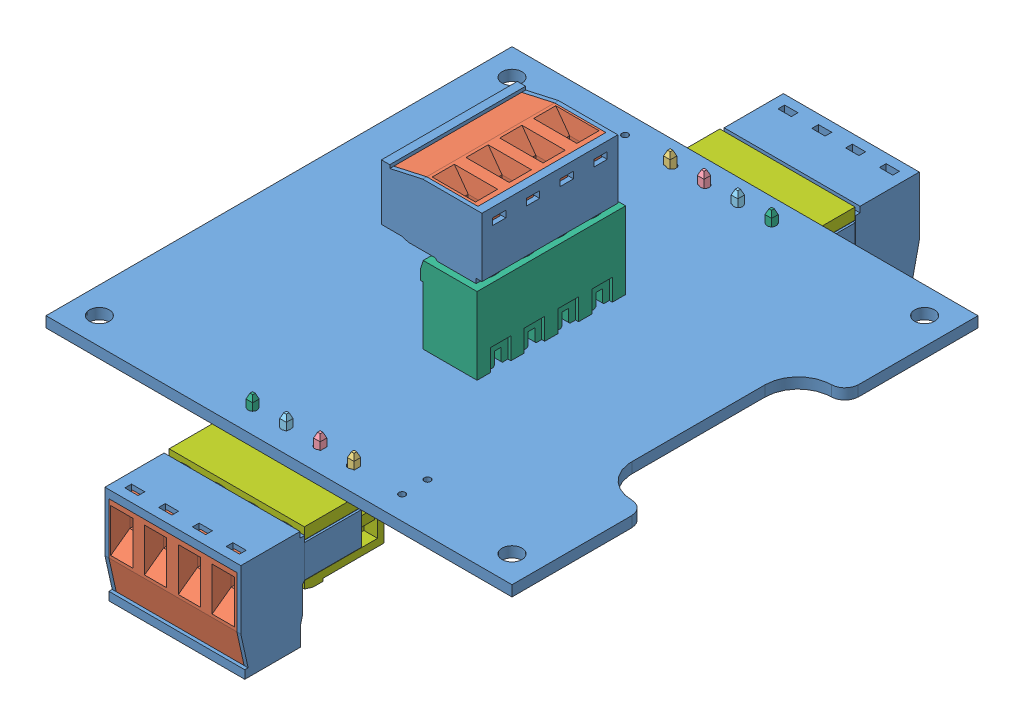
SolidWorks assembly MainBoard, configuration Default. Lengths in mm.
Overall size (70.02 38.08 102.19).
65 component instances, 26 part files, 22 mates.
Components (placement in the parent):
- MainBoard-1: MainBoard [Default] at origin size (70.02 1.6 70.02)
- 691311500104-1: 691311500104 [Default] at (1.7397 7.15 -0.127) x (0 0 1) z (0 1 0) size (22.32 8.5 16)
  - 691311500104_01-1: 691311500104_01 [Default] at origin size (1 1 15)
  - 691311500104_02-1: 691311500104_02 [Default] at origin size (1 1 15)
  - 691311500104_03-1: 691311500104_03 [Default] at origin size (1 1 15)
  - 691311500104_04-1: 691311500104_04 [Default] at origin size (1 1 15)
  - 691311500104_05-1: 691311500104_05 [Default] at origin size (22.32 8.5 12)
- 691351500004-1: 691351500004 [Default] at (1.1147 18.3 -0.127) x (0 0 -1) z (-1 0 0) size (20.42 18.2 15.1)
  - 691351500004_01-1: 691351500004_01 [Default] at origin size (3.9 4.9 7)
  - 691351500004_02-1: 691351500004_02 [Default] at origin size (3.9 4.9 7)
  - 691351500004_03-1: 691351500004_03 [Default] at origin size (3.9 4.9 7)
  - 691351500004_04-1: 691351500004_04 [Default] at origin size (3.9 4.9 7)
  - 691351500004_05-1: 691351500004_05 [Default] at origin size (3.41 13.5 4.75)
  - 691351500004_06-1: 691351500004_06 [Default] at origin size (3.41 13.5 4.75)
  - 691351500004_07-1: 691351500004_07 [Default] at origin size (3.41 13.5 4.75)
  - 691351500004_08-1: 691351500004_08 [Default] at origin size (3.41 13.5 4.75)
  - 691351500004_09-1: 691351500004_09 [Default] at origin size (3.8 3.8 6.92)
  - 691351500004_10-1: 691351500004_10 [Default] at origin size (3.8 3.8 6.92)
  - 691351500004_11-1: 691351500004_11 [Default] at origin size (3.8 3.8 6.92)
  - 691351500004_12-1: 691351500004_12 [Default] at origin size (3.8 3.8 6.92)
  - 691351500004_13-1: 691351500004_13 [Default] at origin size (20.42 18.2 15.1)
  - 691351500004_14-1: 691351500004_14 [Default] at origin size (19.22 3 13.65)
- 691351500004-2: 691351500004 [Default] at (-0.127 -4.675 -46.6672) x (1 0 0) z (0 -1 0) size (20.42 18.2 15.1)
  - 691351500004_01-1: 691351500004_01 [Default] at origin size (3.9 4.9 7)
  - 691351500004_02-1: 691351500004_02 [Default] at origin size (3.9 4.9 7)
  - 691351500004_03-1: 691351500004_03 [Default] at origin size (3.9 4.9 7)
  - 691351500004_04-1: 691351500004_04 [Default] at origin size (3.9 4.9 7)
  - 691351500004_05-1: 691351500004_05 [Default] at origin size (3.41 13.5 4.75)
  - 691351500004_06-1: 691351500004_06 [Default] at origin size (3.41 13.5 4.75)
  - 691351500004_07-1: 691351500004_07 [Default] at origin size (3.41 13.5 4.75)
  - 691351500004_08-1: 691351500004_08 [Default] at origin size (3.41 13.5 4.75)
  - 691351500004_09-1: 691351500004_09 [Default] at origin size (3.8 3.8 6.92)
  - 691351500004_10-1: 691351500004_10 [Default] at origin size (3.8 3.8 6.92)
  - 691351500004_11-1: 691351500004_11 [Default] at origin size (3.8 3.8 6.92)
  - 691351500004_12-1: 691351500004_12 [Default] at origin size (3.8 3.8 6.92)
  - 691351500004_13-1: 691351500004_13 [Default] at origin size (20.42 18.2 15.1)
  - 691351500004_14-1: 691351500004_14 [Default] at origin size (19.22 3 13.65)
- 691351500004-3: 691351500004 [Default] at (0.1164 -4.675 46.6248) x (-1 0 0) z (0 -1 0) size (20.42 18.2 15.1)
  - 691351500004_01-1: 691351500004_01 [Default] at origin size (3.9 4.9 7)
  - 691351500004_02-1: 691351500004_02 [Default] at origin size (3.9 4.9 7)
  - 691351500004_03-1: 691351500004_03 [Default] at origin size (3.9 4.9 7)
  - 691351500004_04-1: 691351500004_04 [Default] at origin size (3.9 4.9 7)
  - 691351500004_05-1: 691351500004_05 [Default] at origin size (3.41 13.5 4.75)
  - 691351500004_06-1: 691351500004_06 [Default] at origin size (3.41 13.5 4.75)
  - 691351500004_07-1: 691351500004_07 [Default] at origin size (3.41 13.5 4.75)
  - 691351500004_08-1: 691351500004_08 [Default] at origin size (3.41 13.5 4.75)
  - 691351500004_09-1: 691351500004_09 [Default] at origin size (3.8 3.8 6.92)
  - 691351500004_10-1: 691351500004_10 [Default] at origin size (3.8 3.8 6.92)
  - 691351500004_11-1: 691351500004_11 [Default] at origin size (3.8 3.8 6.92)
  - 691351500004_12-1: 691351500004_12 [Default] at origin size (3.8 3.8 6.92)
  - 691351500004_13-1: 691351500004_13 [Default] at origin size (20.42 18.2 15.1)
  - 691351500004_14-1: 691351500004_14 [Default] at origin size (19.22 3 13.65)
- 691312510004-1: 691312510004 [Default] at (0.1164 -4.05 35.4748) size (20.32 12 12)
  - 691312510004_01-1: 691312510004_01 [Default] at origin size (1 7.8 9.2)
  - 691312510004_02-1: 691312510004_02 [Default] at origin size (1 7.8 9.2)
  - 691312510004_03-1: 691312510004_03 [Default] at origin size (1 7.8 9.2)
  - 691312510004_04-1: 691312510004_04 [Default] at origin size (1 7.8 9.2)
  - 691312510004_05-1: 691312510004_05 [Default] at origin size (20.32 8.5 12)
- 691312510004-2: 691312510004 [Default] at (-0.127 -4.05 -35.5172) x (-1 0 0) z (0 0 -1) size (20.32 12 12)
  - 691312510004_01-1: 691312510004_01 [Default] at origin size (1 7.8 9.2)
  - 691312510004_02-1: 691312510004_02 [Default] at origin size (1 7.8 9.2)
  - 691312510004_03-1: 691312510004_03 [Default] at origin size (1 7.8 9.2)
  - 691312510004_04-1: 691312510004_04 [Default] at origin size (1 7.8 9.2)
  - 691312510004_05-1: 691312510004_05 [Default] at origin size (20.32 8.5 12)
- Part1^MainBoard-1: Part1^MainBoard [Default] at (-15.494 0 0) x (0 0 -1) z (1 0 0) size (8 8 10) (virtual)
Mates (geometry in assembly coordinates):
- Coincident1: coordinate: point of MainBoard-1; point of assembly
- Coincident2: coincident anti-aligned: plane of MainBoard-1 through (0 1.6 0) normal (0 1 0); plane of 691311500104-1/691311500104_05-1 through (1.7397 1.6 -0.127) normal (0 -1 0)
- Concentric1: concentric anti-aligned: cylinder of 691311500104-1/691311500104_05-1 through (1.5897 2.15 -7.747) axis (0 1 0) radius 3.4; cylinder of 691351500004-1/691351500004_13-1 through (1.5897 13.15 -7.747) axis (0 -1 0) radius 3.1
- Concentric2: concentric anti-aligned: cylinder of 691311500104-1/691311500104_05-1 through (1.5897 2.15 7.493) axis (0 1 0) radius 3.4; cylinder of 691351500004-1/691351500004_13-1 through (1.5897 13.15 7.493) axis (0 -1 0) radius 3.1
- Coincident3: coincident anti-aligned: plane of 691311500104-1/691311500104_05-1 through (-2.3103 13.15 11.033) normal (0 1 0); plane of 691351500004-1/691351500004_13-1 through (1.5897 13.15 7.493) normal (0 -1 0)
- Concentric3: concentric anti-aligned: cylinder of MainBoard-1 through (1.9897 1.6 7.493) axis (0 -1 0) radius 0.6562; circle of 691311500104-1/691311500104_01-1
- Parallel1: parallel anti-aligned: plane of MainBoard-1 through (-35.0097 1.6 0) normal (-1 0 0); plane of 691311500104-1/691311500104_05-1 through (5.7897 13.15 11.033) normal (1 0 0)
- Concentric4: concentric anti-aligned: cylinder of MainBoard-1 through (-7.5036 1.6 31.4748) axis (0 -1 0) radius 0.6456; circle of 691312510004-1/691312510004_04-1
- Concentric5: concentric anti-aligned: cylinder of MainBoard-1 through (7.493 1.6 -31.5172) axis (0 -1 0) radius 0.6562; circle of 691312510004-2/691312510004_04-1
- Parallel2: parallel anti-aligned: plane of MainBoard-1 through (0 1.6 -35.0097) normal (0 0 -1); plane of 691312510004-2/691312510004_05-1 through (-11.287 0 -29.5172) normal (0 0 1)
- Coincident6: coincident anti-aligned: plane of MainBoard-1 through (0 0 0) normal (0 -1 0); plane of 691312510004-2/691312510004_05-1 through (-11.287 0 -41.5172) normal (0 1 0)
- Coincident7: coincident anti-aligned: plane of MainBoard-1 through (0 0 0) normal (0 -1 0); plane of 691312510004-1/691312510004_05-1 through (11.2764 0 41.4748) normal (0 1 0)
- Concentric6: concentric anti-aligned: cylinder of 691351500004-3/691351500004_13-1 through (7.7364 -4.2 41.4748) axis (0 0 -1) radius 3.1; cylinder of 691312510004-1/691312510004_05-1 through (7.7364 -4.2 30.4748) axis (0 0 1) radius 3.4
- Concentric7: concentric anti-aligned: cylinder of 691351500004-3/691351500004_13-1 through (-7.5036 -4.2 41.4748) axis (0 0 -1) radius 3.1; cylinder of 691312510004-1/691312510004_05-1 through (-7.5036 -4.2 30.4748) axis (0 0 1) radius 3.4
- Coincident8: coincident anti-aligned: plane of 691351500004-3/691351500004_13-1 through (2.6564 -4.2 41.4748) normal (0 0 -1); plane of 691312510004-1/691312510004_05-1 through (11.2764 -8.1 41.4748) normal (0 0 1)
- Concentric8: concentric anti-aligned: cylinder of 691351500004-2/691351500004_13-1 through (7.493 -4.2 -41.5172) axis (0 0 1) radius 3.1; cylinder of 691312510004-2/691312510004_05-1 through (7.493 -4.2 -30.5172) axis (0 0 -1) radius 3.4
- Concentric9: concentric anti-aligned: cylinder of 691351500004-2/691351500004_13-1 through (-7.747 -4.2 -41.5172) axis (0 0 1) radius 3.1; cylinder of 691312510004-2/691312510004_05-1 through (-7.747 -4.2 -30.5172) axis (0 0 -1) radius 3.4
- Coincident9: coincident anti-aligned: plane of 691351500004-2/691351500004_13-1 through (7.493 -4.2 -41.5172) normal (0 0 1); plane of 691312510004-2/691312510004_05-1 through (-11.287 -8.1 -41.5172) normal (0 0 -1)
- InPlace1: in place: plane of Part1^MainBoard-1 through (-15.494 0 0) normal (1 0 0); moOrthogonalPlaneRef_w of Part1^MainBoard-1 through (-55 -15.494 0) axis (0 0 1); plane of Part1^MainBoard-1 through (-15.494 0 0) normal (0 0 -1); unknown of Part1^MainBoard-1
- Coincident10: coincident aligned: plane of Part1^MainBoard-1; plane of assembly
- Coincident11: coincident aligned: plane of Part1^MainBoard-1; moOrthogonalPlaneRef_w of assembly
- Coincident12: coincident anti-aligned: plane of Part1^MainBoard-1 through (-15.494 0 0) normal (0 0 -1); moOrthogonalPlaneRef_w of assembly
